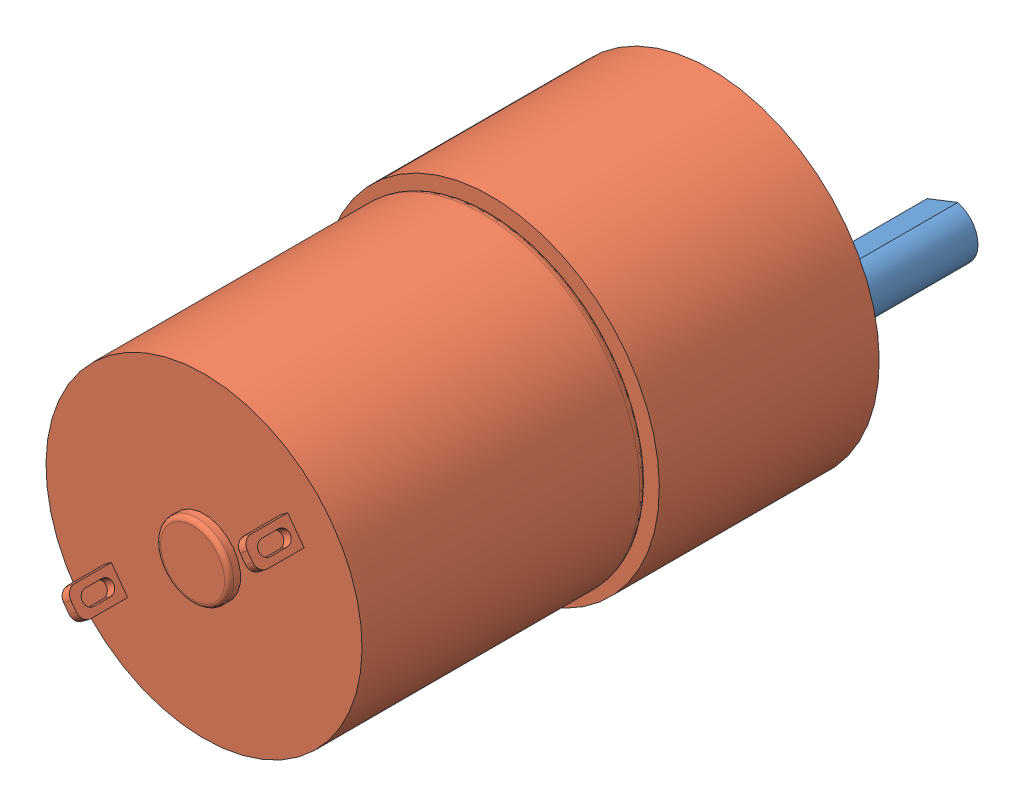
SolidWorks assembly Pololu_GearMotor_37Dmm, configuration Default. Lengths in mm.
Overall size (51.49 51.49 82.3).
2 component instances, 2 part files, 1 mates.
Components (placement in the parent):
- Pololu_ShaftGearMotor6mm-1: Pololu_ShaftGearMotor6mm [Default] at (9.8861 24.7007 16.6991) x (0.930815 0.36549 0) z (0 0 1) size (6 6 22)
- Pololu_GearMotor_37Dmm-1: Pololu_GearMotor_37Dmm [Default] at (5.7082 30.3171 38.6991) x (-0.802354 -0.596848 0) z (0 0 -1) size (36.8 36.8 66.8)
Mates (geometry in assembly coordinates):
- Concentric1: concentric aligned: circle of Pololu_ShaftGearMotor6mm-1; circle of Pololu_GearMotor_37Dmm-1
